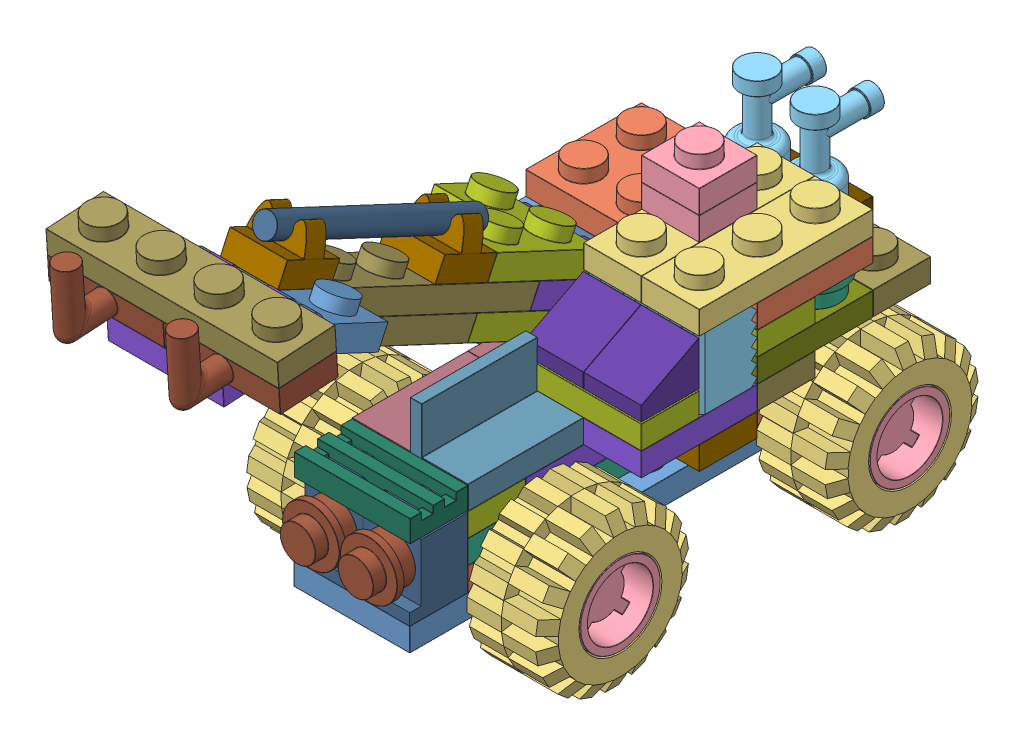
SolidWorks assembly Lift, configuration Default. Lengths in mm.
Overall size (42 65.6 103.41).
61 component instances, 29 part files, 138 mates.
Components (placement in the parent):
- 4211406-1: 4211406 [Default] at (3.9154 1.3814 25.2503) size (15.92 5.02 63.68)
- Wheel Assembly-1: Wheel Assembly [Default] at (3.2744 5.3465 12.922) size (42 29.52 29.52)
  - 4211504-1: 4211504 [Default] at (-7.319 -0.7451 4.3684) size (27.68 6.09 15.92)
  - 4514560-1: 4514560 [Default] at (-18.469 0.3282 0.3884) x (1 0 0) z (0 -0.782052 0.623213) size (11.74 21 21)
  - 4514560-2: 4514560 [Default] at (11.791 0.3282 0.3884) size (11.74 21 21)
  - 4170457-1: 4170457 [Default] at (-12.499 0.3282 0.3884) x (0 1 0) z (0 0 1) size (11 11.84 11)
  - 4170457-2: 4170457 [Default] at (5.821 0.3282 0.3884) x (0 -1 0) z (0 0 1) size (11 11.84 11)
- Wheel Assembly-2: Wheel Assembly [Default] at (3.2744 5.3465 -26.878) size (42 29.52 29.52)
  - 4211504-1: 4211504 [Default] at (-7.319 -0.7451 4.3684) size (27.68 6.09 15.92)
  - 4514560-1: 4514560 [Default] at (-18.469 0.3282 0.3884) x (1 0 0) z (0 -0.782052 0.623213) size (11.74 21 21)
  - 4514560-2: 4514560 [Default] at (11.791 0.3282 0.3884) size (11.74 21 21)
  - 4170457-1: 4170457 [Default] at (-12.499 0.3282 0.3884) x (0 1 0) z (0 0 1) size (11 11.84 11)
  - 4170457-2: 4170457 [Default] at (5.821 0.3282 0.3884) x (0 -1 0) z (0 0 1) size (11 11.84 11)
- 287724-1: 287724 [Default] at (3.9154 7.8214 -30.4697) x (-1 0 0) z (0 0 -1) size (15.92 11.5 7.96)
- 379526-1: 379526 [Default] at (-4.0446 7.8214 17.2903) size (15.92 5.02 47.76)
- 302326-1: 302326 [Default] at (-4.0446 11.0414 17.2903) size (15.92 5.02 7.96)
- 302224-1: 302224 [Default] at (-4.0446 11.0414 9.3303) size (15.92 5.02 15.92)
- 302224-2: 302224 [Default] at (-4.0446 11.0414 -14.5497) size (15.92 5.02 15.92)
- 371024-1: 371024 [Default] at (-12.0046 11.0414 -6.5897) size (31.84 5.02 7.96)
- 407026-1: 407026 [Default] at (-4.0446 4.6014 25.2503) x (0 0 -1) z (1 0 0) size (7.96 11.34 7.96)
- 407026-2: 407026 [Default] at (3.9154 4.6014 25.2503) x (0 0 -1) z (1 0 0) size (7.96 11.34 7.96)
- 3005744-1: 3005744 [Default] at (3.9154 10.1614 27.6753) x (0.999152 -0.041165 0) z (-0.041165 -0.999152 0) size (7.8 5.02 7.8)
- 3005744-2: 3005744 [Default] at (-4.0446 10.1614 27.6753) x (0.979514 -0.201376 0) z (-0.201376 -0.979514 0) size (7.8 5.02 7.8)
- 302326-2: 302326 [Default] at (-4.0446 14.2614 -22.5097) size (15.92 5.02 7.96)
- 4211001-1: 4211001 [Default] at (-12.0046 14.2614 -14.5497) size (31.84 5.02 7.96)
- 306924-1: 306924 [Default] at (-4.0446 14.2614 1.3703) x (0 0 -1) z (1 0 0) size (15.92 3.22 7.96)
- 306924-2: 306924 [Default] at (-4.0446 14.2614 17.2903) x (0 0 -1) z (1 0 0) size (15.92 3.22 7.96)
- 486524-1: 486524 [Default] at (3.9154 14.2614 17.2403) x (0 0 -1) z (1 0 0) size (15.92 9.6 7.96)
- 4211350-2: 4211350 [Default] at (-4.0446 14.1414 25.2003) size (15.92 3.22 7.96)
- 302224-3: 302224 [Default] at (3.9154 14.2614 1.3703) size (15.92 5.02 15.92)
- 4211065-1: 4211065 [Default] at (-12.0046 17.4814 -14.5497) size (31.84 5.02 15.92)
- 4211001-2: 4211001 [Default] at (-12.0046 17.5214 -30.4697) size (31.84 5.02 7.96)
- 302326-3: 302326 [Default] at (3.9154 17.4814 1.3703) size (15.92 5.02 7.96)
- 302326-4: 302326 [Default] at (3.9154 20.7014 -14.5497) size (15.92 5.02 7.96)
- 287724-2: 287724 [Default] at (11.8754 17.4814 -6.5897) x (-1 0 0) z (0 0 -1) size (15.92 11.5 7.96)
- 4244368-1: 4244368 [Default] at (11.8754 20.7014 1.3703) size (7.96 6.27 7.96)
- 4244368-2: 4244368 [Default] at (3.9154 20.7014 1.3703) size (7.96 6.27 7.96)
- 4211094-1: 4211094 [Default] at (-4.0446 20.7414 -22.5097) size (15.92 5.02 15.92)
- 4244627-1: 4244627 [Default] at (-12.0046 20.7014 -14.5497) size (15.92 5.02 13.96)
- 302024-1: 302024 [Default] at (-12.0046 23.9214 -14.5497) size (31.84 5.02 15.92)
- 362324-1: 362324 [Default] at (11.8754 27.1414 -6.5897) x (0 0 -1) z (1 0 0) size (23.88 5.02 7.96)
- 3000841-1: 3000841 [Default] at (3.9154 30.3614 -14.5497) size (7.96 5.02 7.96)
- 362324-3: 362324 [Default] at (3.9154 27.1414 -6.5897) x (0 0 -1) z (1 0 0) size (23.88 5.02 7.96)
- 3000841-3: 3000841 [Default] at (3.9154 33.5814 -14.5497) size (7.96 5.02 7.96)
- 4211503-1: 4211503 [Default] at (-4.0446 23.9614 -30.4697) x (-1 0 0) z (0 0 -1) size (6.5 11.42 11.15)
- 4211503-2: 4211503 [Default] at (3.9154 23.9614 -30.4697) x (-1 0 0) z (0 0 -1) size (6.5 11.42 11.15)
- 4211525-1: 4211525 [Default] at (-12.0046 20.7014 -22.5097) x (0.72441 0 0.689369) z (-0.689369 0 0.72441) size (7.8 5.02 7.8)
- 4211525-2: 4211525 [Default] at (11.8754 20.7014 -22.5097) size (7.8 5.02 7.8)
- 4211001-3: 4211001 [Default] at (-4.0446 38.1669 38.5401) x (0 -0.424334 -0.905506) z (1 0 0) size (31.84 5.02 7.96)
- 4210635-1: 4210635 [Default] at (-4.0446 21.2784 2.501) x (-1 0 0) z (0 -0.424334 -0.905506) size (15.92 5.02 15.92)
- 4211001-4: 4211001 [Default] at (-4.0446 27.5719 8.3425) x (0 0.424334 0.905506) z (-1 0 0) size (31.84 5.02 7.96)
- 4519849-1: 4519849 [Default] at (-4.0446 24.1942 1.1346) x (-1 0 0) z (0 -0.424334 -0.905506) size (15.92 6 12.56)
- 4244627-2: 4244627 [Default] at (-4.0446 41.0826 37.1738) x (1 0 0) z (0 0.424334 0.905506) size (15.92 5.02 13.96)
- 4211069-1: 4211069 [Default] at (-4.0446 43.9984 35.8074) x (1 0 0) z (0 0.424334 0.905506) size (8.47 6.96 7.96)
- 4211069-2: 4211069 [Default] at (-4.0446 33.8653 14.1839) x (1 0 0) z (0 0.424334 0.905506) size (8.47 6.96 7.96)
- 4211628-1: 4211628 [Default] at (-4.0446 36.7476 8.1508) x (0.996533 -0.075334 0.035303) z (-0.083196 -0.902367 0.422863) size (3.2 32.1 3.2)
- 4210635-2: 4210635 [Default] at (-4.0446 27.1099 -0.2317) x (-1 0 0) z (0 -0.424334 -0.905506) size (15.92 5.02 15.92)
- 4519849-2: 4519849 [Default] at (3.9154 43.6592 50.7884) x (-1 0 0) z (0 0.064103 -0.997943) size (15.92 6 12.56)
- 4501109-1: 4501109 [Default] at (3.9154 46.8726 50.9948) x (1 0 0) z (0 -0.064103 0.997943) size (15.92 9.46 14.57)
- 4501109-2: 4501109 [Default] at (-12.0046 46.8726 50.9948) x (1 0 0) z (0 -0.064103 0.997943) size (15.92 9.46 14.57)
- 4211001-5: 4211001 [Default] at (11.8754 50.086 51.2013) x (-1 0 0) z (0 0.064103 -0.997943) size (31.84 5.02 7.96)
Mates (geometry in assembly coordinates):
- Concentric1: concentric aligned: cylinder of 4211406-1; cylinder of Wheel Assembly-1/4211504-1
- Concentric2: concentric aligned: cylinder of 4211406-1; cylinder of Wheel Assembly-1/4211504-1
- Concentric3: concentric aligned: cylinder of 4211406-1; cylinder of Wheel Assembly-2/4211504-1
- Concentric4: concentric aligned: cylinder of 4211406-1; cylinder of Wheel Assembly-2/4211504-1
- Coincident1: coincident anti-aligned: plane of 4211406-1 through (7.8954 4.6014 29.2303) normal (0 1 0); plane of Wheel Assembly-1/4211504-1 through (-0.0646 4.6014 21.2703) normal (0 -1 0)
- Coincident2: coincident anti-aligned: plane of 4211406-1 through (7.8954 4.6014 29.2303) normal (0 1 0); plane of Wheel Assembly-2/4211504-1 through (-0.0646 4.6014 -18.5297) normal (0 -1 0)
- Concentric5: concentric aligned: cylinder of Wheel Assembly-2/4211504-1; cylinder of 287724-1
- Concentric6: concentric aligned: cylinder of Wheel Assembly-2/4211504-1; cylinder of 287724-1
- Coincident3: coincident anti-aligned: plane of Wheel Assembly-2/4211504-1 through (-0.0646 7.8214 -18.5297) normal (0 1 0); plane of 287724-1 through (-0.0646 7.8214 -34.4497) normal (0 -1 0)
- Concentric7: concentric aligned: cylinder of Wheel Assembly-2/4211504-1; cylinder of 379526-1
- Concentric8: concentric aligned: cylinder of Wheel Assembly-1/4211504-1; cylinder of 379526-1
- Coincident4: coincident anti-aligned: plane of Wheel Assembly-1/4211504-1 through (-0.0646 7.8214 21.2703) normal (0 1 0); plane of 379526-1 through (-0.0646 7.8214 21.2703) normal (0 -1 0)
- Concentric9: concentric aligned: cylinder of 379526-1; cylinder of 302326-1
- Concentric10: concentric aligned: cylinder of 379526-1; cylinder of 302326-1
- Coincident5: coincident anti-aligned: plane of 379526-1 through (-0.0646 11.0414 21.2703) normal (0 1 0); plane of 302326-1 through (-0.0646 11.0414 21.2703) normal (0 -1 0)
- Concentric11: concentric aligned: cylinder of 379526-1; cylinder of 302224-1
- Concentric12: concentric aligned: cylinder of 379526-1; cylinder of 302224-1
- Concentric13: concentric aligned: cylinder of 379526-1; cylinder of 302224-2
- Concentric14: concentric aligned: cylinder of 379526-1; cylinder of 302224-2
- Concentric15: concentric aligned: cylinder of 379526-1; cylinder of 371024-1
- Concentric16: concentric aligned: cylinder of 379526-1; cylinder of 371024-1
- Coincident6: coincident anti-aligned: plane of 379526-1 through (-0.0646 11.0414 21.2703) normal (0 1 0); plane of 302224-1 through (-0.0646 11.0414 13.3103) normal (0 -1 0)
- Coincident7: coincident anti-aligned: plane of 379526-1 through (-0.0646 11.0414 21.2703) normal (0 1 0); plane of 302224-2 through (-0.0646 11.0414 -10.5697) normal (0 -1 0)
- Coincident8: coincident anti-aligned: plane of 379526-1 through (-0.0646 11.0414 21.2703) normal (0 1 0); plane of 371024-1 through (-8.0246 11.0414 -2.6097) normal (0 -1 0)
- Coincident9: coincident aligned: plane of 407026-2 through (7.8954 14.1414 29.2303) normal (1 0 0); plane of 4211406-1 through (7.8954 4.6014 21.2703) normal (1 0 0)
- Coincident10: coincident aligned: plane of 407026-1 through (-8.0246 14.1414 29.2303) normal (-1 0 0); plane of 4211406-1 through (-8.0246 4.6014 21.2703) normal (-1 0 0)
- Coincident11: coincident aligned: plane of 4211406-1 through (-0.0646 4.6014 29.2303) normal (0 0 1); plane of 407026-1 through (-8.0246 14.1414 29.2303) normal (0 0 1)
- Coincident12: coincident aligned: plane of 4211406-1 through (-0.0646 4.6014 29.2303) normal (0 0 1); plane of 407026-2 through (-0.0646 14.1414 29.2303) normal (0 0 1)
- Coincident13: coincident anti-aligned: plane of 4211406-1 through (7.8954 4.6014 29.2303) normal (0 1 0); plane of 407026-2 through (7.8954 4.6014 21.2703) normal (0 -1 0)
- Coincident14: coincident anti-aligned: plane of 4211406-1 through (7.8954 4.6014 29.2303) normal (0 1 0); plane of 407026-1 through (-0.0646 4.6014 21.2703) normal (0 -1 0)
- Concentric18: concentric aligned: cylinder of 3005744-1; cylinder of 407026-2
- Concentric19: concentric aligned: cylinder of 3005744-2; cylinder of 407026-1
- Coincident15: coincident anti-aligned: plane of 407026-2 through (-0.0646 6.2014 27.6753) normal (0 0 1); plane of 3005744-1 through (3.9154 10.1614 27.6753) normal (0 0 -1)
- Coincident16: coincident anti-aligned: plane of 407026-1 through (-8.0246 6.2014 27.6753) normal (0 0 1); plane of 3005744-2 through (-4.0446 10.1614 27.6753) normal (0 0 -1)
- Concentric20: concentric aligned: cylinder of 302224-2; cylinder of 302326-2
- Concentric21: concentric aligned: cylinder of 302224-2; cylinder of 302326-2
- Coincident20: coincident anti-aligned: plane of 302224-2 through (-0.0646 14.2614 -10.5697) normal (0 1 0); plane of 302326-2 through (-0.0646 14.2614 -18.5297) normal (0 -1 0)
- Concentric22: concentric aligned: cylinder of 302224-2; cylinder of 4211001-1
- Concentric23: concentric aligned: cylinder of 302224-2; cylinder of 4211001-1
- Coincident21: coincident anti-aligned: plane of 302224-2 through (-0.0646 14.2614 -10.5697) normal (0 1 0); plane of 4211001-1 through (-8.0246 14.2614 -10.5697) normal (0 -1 0)
- Coincident22: coincident anti-aligned: plane of 4211001-1 through (-15.9846 17.4814 -10.5697) normal (0 0 1); plane of 306924-1 through (-8.0246 17.4814 -10.5697) normal (0 0 -1)
- Coincident23: coincident aligned: plane of 302224-1 through (-8.0246 14.2614 5.3503) normal (-1 0 0); plane of 306924-1 through (-8.0246 17.4814 5.3503) normal (-1 0 0)
- Coincident24: coincident anti-aligned: plane of 371024-1 through (-8.0246 14.2614 -2.6097) normal (0 1 0); plane of 306924-1 through (-0.0646 14.2614 -2.6097) normal (0 -1 0)
- Coincident25: coincident aligned: plane of 486524-1 through (7.8954 17.4814 21.2203) normal (1 0 0); plane of 302326-1 through (7.8954 14.2614 13.3103) normal (1 0 0)
- Coincident26: coincident aligned: plane of 407026-2 through (7.8954 14.1414 29.2303) normal (1 0 0); plane of 4211350-2 through (7.8954 17.3614 21.2203) normal (1 0 0)
- Coincident30: coincident anti-aligned: plane of 407026-2 through (7.8954 14.1414 21.2703) normal (0 1 0); plane of 4211350-2 through (-0.0646 14.1414 29.1803) normal (0 -1 0)
- Coincident32: coincident anti-aligned: line of 407026-2; line of 4211350-2
- Coincident33: coincident anti-aligned: plane of 486524-1 through (-0.0646 17.4814 21.2203) normal (0 0 1); plane of 4211350-2 through (-8.0246 17.3614 21.2203) normal (0 0 -1)
- Coincident34: coincident anti-aligned: plane of 302326-1 through (-0.0646 14.2614 21.2703) normal (0 1 0); plane of 486524-1 through (7.8954 14.2614 13.2603) normal (0 -1 0)
- Concentric24: concentric aligned: cylinder of 302224-1; cylinder of 302224-3
- Concentric25: concentric aligned: cylinder of 371024-1; cylinder of 302224-3
- Coincident35: coincident anti-aligned: plane of 302224-1 through (-0.0646 14.2614 13.3103) normal (0 1 0); plane of 302224-3 through (7.8954 14.2614 5.3503) normal (0 -1 0)
- Concentric26: concentric aligned: cylinder of 287724-1; cylinder of 4211001-2
- Concentric27: concentric aligned: cylinder of 287724-1; cylinder of 4211001-2
- Concentric28: concentric aligned: cylinder of 302326-2; cylinder of 4211065-1
- Concentric29: concentric aligned: cylinder of 4211001-1; cylinder of 4211065-1
- Coincident36: coincident anti-aligned: plane of 287724-1 through (-0.0646 17.5214 -34.4497) normal (0 1 0); plane of 4211001-2 through (-8.0246 17.5214 -26.4897) normal (0 -1 0)
- Coincident37: coincident anti-aligned: plane of 4211001-1 through (-8.0246 17.4814 -10.5697) normal (0 1 0); plane of 4211065-1 through (-8.0246 17.4814 -10.5697) normal (0 -1 0)
- Concentric30: concentric aligned: cylinder of 302224-3; cylinder of 302326-3
- Concentric31: concentric aligned: cylinder of 302224-3; cylinder of 302326-3
- Coincident38: coincident anti-aligned: plane of 302224-3 through (7.8954 17.4814 5.3503) normal (0 1 0); plane of 302326-3 through (7.8954 17.4814 5.3503) normal (0 -1 0)
- Concentric32: concentric aligned: cylinder of 4211065-1; cylinder of 302326-4
- Concentric33: concentric aligned: cylinder of 4211065-1; cylinder of 302326-4
- Coincident39: coincident anti-aligned: plane of 4211065-1 through (-8.0246 20.7014 -10.5697) normal (0 1 0); plane of 302326-4 through (7.8954 20.7014 -10.5697) normal (0 -1 0)
- Concentric34: concentric aligned: cylinder of 302224-3; cylinder of 287724-2
- Concentric35: concentric aligned: cylinder of 302224-3; cylinder of 287724-2
- Coincident40: coincident anti-aligned: plane of 302224-3 through (7.8954 17.4814 5.3503) normal (0 1 0); plane of 287724-2 through (7.8954 17.4814 -10.5697) normal (0 -1 0)
- Coincident41: coincident aligned: plane of 302326-3 through (15.8554 20.7014 -2.6097) normal (1 0 0); plane of 4244368-1 through (15.8554 27.0014 -2.6097) normal (1 0 0)
- Coincident42: coincident aligned: plane of 302326-3 through (-0.0646 20.7014 5.3503) normal (0 0 1); plane of 4244368-1 through (7.8954 27.0014 5.3503) normal (0 0 1)
- Coincident43: coincident anti-aligned: plane of 302326-3 through (7.8954 20.7014 5.3503) normal (0 1 0); plane of 4244368-1 through (15.8554 20.7014 5.3503) normal (0 -1 0)
- Concentric36: concentric aligned: cylinder of 4211065-1; cylinder of 4211094-1
- Concentric37: concentric aligned: cylinder of 4211001-2; cylinder of 4211094-1
- Coincident44: coincident anti-aligned: plane of 4211001-2 through (-8.0246 20.7414 -26.4897) normal (0 1 0); plane of 4211094-1 through (-0.0646 20.7414 -18.5297) normal (0 -1 0)
- Concentric38: concentric aligned: cylinder of 4211065-1; cylinder of 4244627-1
- Concentric39: concentric aligned: cylinder of 4211065-1; cylinder of 4244627-1
- Coincident45: coincident anti-aligned: plane of 4211065-1 through (-8.0246 20.7014 -10.5697) normal (0 1 0); plane of 4244627-1 through (-8.0246 20.7014 -10.5697) normal (0 -1 0)
- Concentric41: concentric aligned: cylinder of 302326-4; cylinder of 302024-1
- Concentric42: concentric aligned: cylinder of 4244627-1; cylinder of 302024-1
- Coincident46: coincident anti-aligned: plane of 302326-4 through (7.8954 23.9214 -10.5697) normal (0 1 0); plane of 302024-1 through (-8.0246 23.9214 -10.5697) normal (0 -1 0)
- Concentric43: concentric aligned: cylinder of 302024-1; cylinder of 362324-1
- Concentric44: concentric aligned: cylinder of 287724-2; cylinder of 362324-1
- Coincident47: coincident anti-aligned: plane of 302024-1 through (-8.0246 27.1414 -10.5697) normal (0 1 0); plane of 362324-1 through (15.8554 27.1414 -10.5697) normal (0 -1 0)
- Concentric47: concentric aligned: cylinder of 302024-1; cylinder of 362324-3
- Concentric48: concentric aligned: cylinder of 287724-2; cylinder of 362324-3
- Coincident52: coincident anti-aligned: plane of 3000841-1 through (7.8954 33.5814 -10.5697) normal (0 1 0); plane of 3000841-3 through (7.8954 33.5814 -10.5697) normal (0 -1 0)
- Coincident53: coincident aligned: plane of 3000841-1 through (7.8954 33.5814 -18.5297) normal (1 0 0); plane of 3000841-3 through (7.8954 36.8014 -18.5297) normal (1 0 0)
- Coincident54: coincident aligned: plane of 3000841-1 through (-0.0646 33.5814 -10.5697) normal (0 0 1); plane of 3000841-3 through (-0.0646 36.8014 -10.5697) normal (0 0 1)
- Concentric49: concentric aligned: cylinder of 362324-3; cylinder of 3000841-3
- Coincident55: coincident aligned: plane of 3000841-1 through (7.8954 33.5814 -18.5297) normal (1 0 0); plane of 362324-3 through (7.8954 30.3614 -2.6097) normal (1 0 0)
- Coincident56: coincident anti-aligned: plane of 3000841-1 through (7.8954 30.3614 -10.5697) normal (0 -1 0); plane of 362324-3 through (7.8954 30.3614 -10.5697) normal (0 1 0)
- Coincident58: coincident anti-aligned: plane of 302024-1 through (-8.0246 27.1414 -10.5697) normal (0 1 0); plane of 362324-3 through (7.8954 27.1414 -10.5697) normal (0 -1 0)
- Concentric50: concentric aligned: cylinder of 4211065-1; cylinder of 4211525-2
- Coincident59: coincident anti-aligned: plane of 4211065-1 through (-8.0246 20.7014 -10.5697) normal (0 1 0); plane of 4211525-2 through (11.8754 20.7014 -22.5097) normal (0 -1 0)
- Concentric51: concentric aligned: cylinder of 4211065-1; cylinder of 4211525-1
- Coincident60: coincident anti-aligned: plane of 4211065-1 through (-8.0246 20.7014 -10.5697) normal (0 1 0); plane of 4211525-1 through (-12.0046 20.7014 -22.5097) normal (0 -1 0)
- Coincident61: coincident anti-aligned: plane of 4211094-1 through (-0.0646 23.9614 -18.5297) normal (0 1 0); plane of 4211503-2 through (3.9154 23.9614 -30.4697) normal (0 -1 0)
- Concentric52: concentric aligned: cylinder of 4211094-1; cylinder of 4211503-2
- Parallel1: parallel aligned: plane of 4211094-1 through (-8.0246 23.9614 -34.4497) normal (0 0 -1); plane of 4211503-2 through (3.9154 31.9814 -38.3697) normal (0 0 -1)
- Coincident63: coincident anti-aligned: plane of 4211094-1 through (-0.0646 23.9614 -18.5297) normal (0 1 0); plane of 4211503-1 through (-4.0446 23.9614 -30.4697) normal (0 -1 0)
- Concentric54: concentric aligned: cylinder of 4211094-1; cylinder of 4211503-1
- Parallel2: parallel aligned: plane of 4211094-1 through (-8.0246 23.9614 -34.4497) normal (0 0 -1); plane of 4211503-1 through (-4.0446 31.9814 -38.3697) normal (0 0 -1)
- Coincident65: coincident anti-aligned: plane of 4211001-3 through (-8.0246 29.2607 11.9464) normal (0 -0.424334 -0.905506); plane of 4210635-1 through (-0.0646 29.2607 11.9464) normal (0 0.424334 0.905506)
- Coincident66: coincident aligned: plane of 4211001-3 through (-8.0246 42.7715 40.7777) normal (-1 0 0); plane of 4210635-1 through (-8.0246 29.2607 11.9464) normal (-1 0 0)
- Coincident67: coincident aligned: plane of 4211001-3 through (-0.0646 39.3938 33.5698) normal (0 0.905506 -0.424334); plane of 4210635-1 through (-8.0246 22.5053 -2.4693) normal (0 0.905506 -0.424334)
- Concentric55: concentric aligned: cylinder of 4210635-1; cylinder of 4211001-4
- Concentric56: concentric aligned: cylinder of 4211001-3; cylinder of 4211001-4
- Coincident68: coincident anti-aligned: plane of 4211001-3 through (-0.0646 39.3938 33.5698) normal (0 0.905506 -0.424334); plane of 4211001-4 through (-8.0246 29.2607 11.9464) normal (0 -0.905506 0.424334)
- Concentric57: concentric aligned: cylinder of 4210635-1; cylinder of 4519849-1
- Concentric58: concentric aligned: cylinder of 4210635-1; cylinder of 4519849-1
- Coincident69: coincident anti-aligned: plane of 4210635-1 through (-8.0246 22.5053 -2.4693) normal (0 0.905506 -0.424334); plane of 4519849-1 through (-8.0246 22.5053 -2.4693) normal (0 -0.905506 0.424334)
- Concentric59: concentric aligned: cylinder of 4211001-3; cylinder of 4244627-2
- Coincident70: coincident aligned: plane of 4211001-3 through (-8.0246 42.7715 40.7777) normal (-1 0 0); plane of 4244627-2 through (-8.0246 42.3095 32.2035) normal (-1 0 0)
- Coincident71: coincident anti-aligned: plane of 4211001-3 through (-0.0646 39.3938 33.5698) normal (0 0.905506 -0.424334); plane of 4244627-2 through (-0.0646 42.7715 40.7777) normal (0 -0.905506 0.424334)
- Concentric60: concentric aligned: cylinder of 4519849-1; cylinder of 4244627-1
- Coincident72: coincident aligned: plane of 4244627-1 through (-15.9846 23.9214 -18.5297) normal (-1 0 0); plane of 4519849-1 through (-15.9846 28.7987 3.3722) normal (-1 0 0)
- Coincident74: coincident anti-aligned: plane of 4244627-2 through (-0.0646 45.6872 39.4113) normal (0 0.905506 -0.424334); plane of 4211069-1 through (-0.0646 45.6872 39.4113) normal (0 -0.905506 0.424334)
- Coincident75: coincident aligned: plane of 4211001-4 through (-0.0646 28.7987 3.3722) normal (1 0 0); plane of 4211069-1 through (-0.0646 45.2253 30.8371) normal (1 0 0)
- Coincident76: coincident aligned: plane of 4244627-2 through (-8.0246 42.3095 32.2035) normal (0 -0.424334 -0.905506); plane of 4211069-1 through (-8.0246 45.2253 30.8371) normal (0 -0.424334 -0.905506)
- Coincident77: coincident aligned: plane of 4211001-4 through (-8.0246 28.7987 3.3722) normal (-1 0 0); plane of 4211069-2 through (-8.0246 35.0922 9.2137) normal (-1 0 0)
- Coincident78: coincident anti-aligned: plane of 4211001-4 through (-8.0246 32.1764 10.58) normal (0 0.905506 -0.424334); plane of 4211069-2 through (-0.0646 35.5541 17.7878) normal (0 -0.905506 0.424334)
- Distance1: distance = 7.96 mm anti-aligned: plane of 4211069-2 through (-8.0246 35.0922 9.2137) normal (0 -0.424334 -0.905506); plane of 4519849-1 through (-0.0646 28.7987 3.3722) normal (0 0.424334 0.905506)
- Concentric61: concentric anti-aligned: cylinder of 4211069-1; cylinder of 4211628-1
- Coincident80: coincident aligned: plane of 4211069-1 through (-8.0246 48.6029 38.045) normal (0 0.424334 0.905506); plane of 4211628-1 through (-4.0446 50.3687 37.2175) normal (0 0.424334 0.905506)
- Concentric62: concentric aligned: cylinder of 4211001-4; cylinder of 4210635-2
- Concentric63: concentric aligned: cylinder of 4519849-1; cylinder of 4210635-2
- Coincident81: coincident anti-aligned: plane of 4519849-1 through (-8.0246 25.421 -3.8356) normal (0 0.905506 -0.424334); plane of 4210635-2 through (-8.0246 25.421 -3.8356) normal (0 -0.905506 0.424334)
- Coincident82: coincident aligned: plane of 4501109-2 through (-15.9846 49.8309 55.1731) normal (0 -0.064103 0.997943); plane of 4519849-2 through (7.8954 46.6175 54.9667) normal (0 -0.064103 0.997943)
- Concentric64: concentric aligned: cylinder of 4519849-2; cylinder of 4501109-2
- Coincident83: coincident anti-aligned: plane of 4519849-2 through (-0.0646 47.1277 47.023) normal (0 0.997943 0.064103); plane of 4501109-2 through (-8.0246 46.6175 54.9667) normal (0 -0.997943 -0.064103)
- Concentric65: concentric aligned: cylinder of 4519849-2; cylinder of 4501109-1
- Coincident84: coincident aligned: plane of 4519849-2 through (7.8954 46.6175 54.9667) normal (0 -0.064103 0.997943); plane of 4501109-1 through (-0.0646 49.8309 55.1731) normal (0 -0.064103 0.997943)
- Coincident85: coincident anti-aligned: plane of 4519849-2 through (-0.0646 47.1277 47.023) normal (0 0.997943 0.064103); plane of 4501109-1 through (7.8954 46.6175 54.9667) normal (0 -0.997943 -0.064103)
- Concentric66: concentric aligned: cylinder of 4501109-1; cylinder of 4211001-5
- Concentric67: concentric aligned: cylinder of 4501109-2; cylinder of 4211001-5
- Coincident86: coincident anti-aligned: plane of 4501109-2 through (-8.0246 49.8309 55.1731) normal (0 0.997943 0.064103); plane of 4211001-5 through (7.8954 50.3411 47.2294) normal (0 -0.997943 -0.064103)
- Concentric68: concentric aligned: cylinder of 4519849-2; cylinder of 4244627-2
- Coincident87: coincident aligned: unknown of 4244627-2; unknown of 4519849-2
- LocalLPattern2: unknown: unknown of 302326-3
